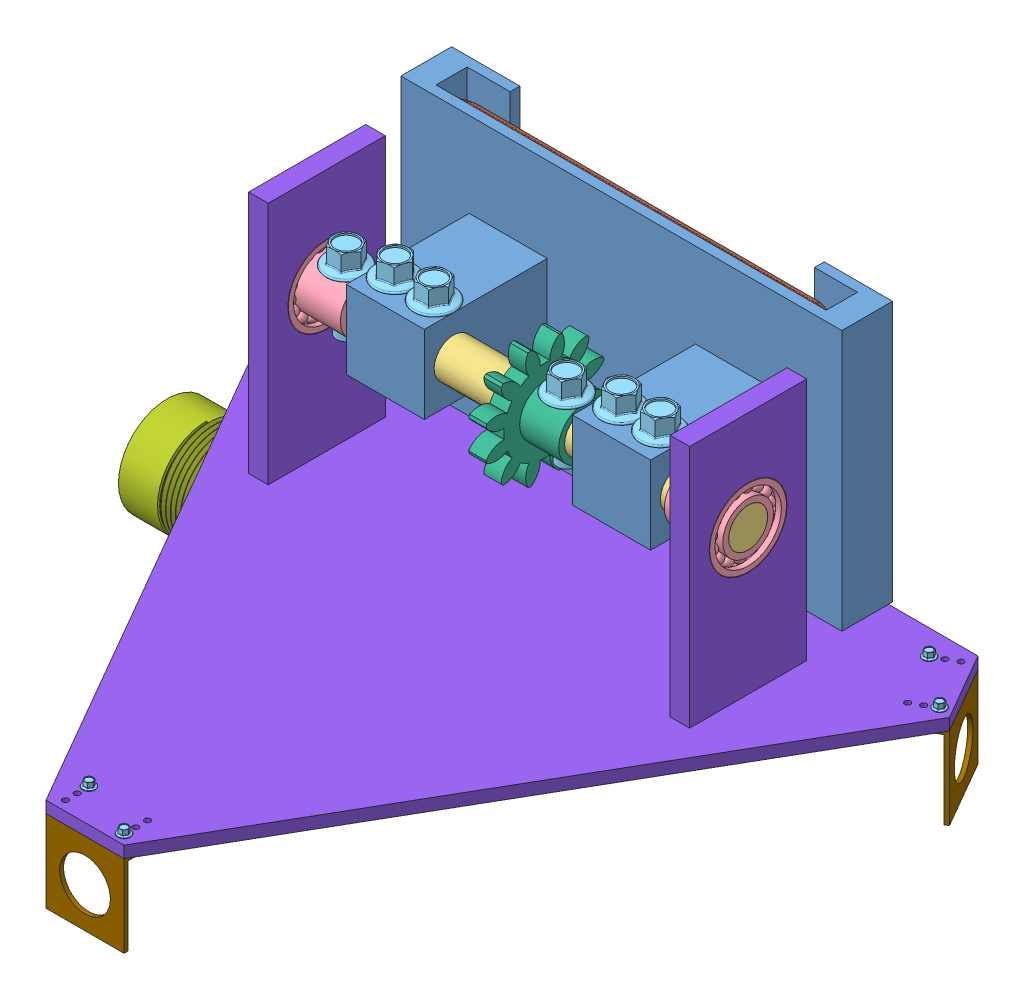
SolidWorks assembly Final Assembly, configuration Default. Lengths in mm.
Overall size (358.9 208.33 302.86).
26 component instances, 9 part files, 2 mates.
Components (placement in the parent):
- Assem2-1: Assem2 [Default] at (73.9795 152.7864 155.2771) size (297.05 208.33 104.25)
  - panpart1-1: panpart1 [Default] at (50.4862 130.7622 195.8282) size (226 133.5 89)
  - tablet-1: tablet [Default] at (50.8522 130.6632 215.8282) size (200.66 129.98 23.56)
  - shaft-1: shaft [Default] at (-62.5138 130.7622 269.8282) x (1 0 0) z (0 0 -1) size (226 20 20)
  - Bearing-1: Bearing [Default] at (-1.8143 116.4662 250.1482) size (30 40 40)
  - Bearing-2: Bearing [Default] at (102.7866 145.0582 250.1482) x (-1 0 0) z (0 0 1) size (30 40 40)
  - hex flange machine screw_am-1: hex flange machine screw_am [B18.6.7M - M10 x 1.5 x 30 Indented HFMS --30N] at (-42.5138 154.4622 269.8282) x (0 -1 0) z (0 0 1) size (40.7 21 21)
  - hex flange machine screw_am-2: hex flange machine screw_am [B18.6.7M - M10 x 1.5 x 30 Indented HFMS --30N] at (143.4862 154.4622 269.8282) x (0 -1 0) z (-0.357498 0 0.933914) size (40.7 21 21)
  - hex flange machine screw_am-3: hex flange machine screw_am [B18.6.7M - M10 x 1.5 x 30 Indented HFMS --30N] at (-17.5138 161.4622 269.8282) x (0 -1 0) z (-0.737651 0 0.675182) size (40.7 21 21)
  - hex flange machine screw_am-4: hex flange machine screw_am [B18.6.7M - M10 x 1.5 x 30 Indented HFMS --30N] at (2.4862 161.4622 269.8282) x (0 -1 0) z (0 0 1) size (40.7 21 21)
  - hex flange machine screw_am-5: hex flange machine screw_am [B18.6.7M - M10 x 1.5 x 30 Indented HFMS --30N] at (98.4862 161.4622 269.8282) x (0 -1 0) z (0 0 1) size (40.7 21 21)
  - hex flange machine screw_am-6: hex flange machine screw_am [B18.6.7M - M10 x 1.5 x 30 Indented HFMS --30N] at (118.4862 161.4622 269.8282) x (0 -1 0) z (0 0 1) size (40.7 21 21)
  - Gear-1: Gear [Default] at (321.6356 216.6863 318.7793) x (1 0 0) z (0 0 -1) size (28.89 60.5 60.5)
  - hex flange machine screw_am-8: hex flange machine screw_am [B18.6.7M - M10 x 1.5 x 30 Indented HFMS --30N] at (70.4862 154.4622 269.8282) x (0 -1 0) z (0 0 1) size (40.7 21 21)
  - worm-1: worm [Default] at (-113.563 14.8313 270.5485) size (110 50 52.57)
- Assem1-1: Assem1 [Default] at (5281.6766 -25045.8049 41757.6662) x (-1 0 0) z (0 0 -1) size (349.71 173 302.86)
  - Base-1: Base [Default] at (5157.2109 25249.3535 41296.0137) size (349.71 131 302.86)
  - LClamp-1: LClamp [Default] at (5001.4077 25249.3535 41362.8727) x (0.5 0 0.866025) z (0.866025 0 -0.5) size (40 42 22)
  - LClamp-2: LClamp [Default] at (5177.2109 25249.3535 41127.6547) x (-1 0 0) z (0 0 1) size (40 42 22)
  - LClamp-3: LClamp [Default] at (5293.0141 25249.3535 41397.5137) x (0.5 0 -0.866025) z (-0.866025 0 -0.5) size (40 42 22)
  - hex flange machine screw_am-1: hex flange machine screw_am [B18.6.7M - M3 x 0.5 x 10 Indented HFMS --10N] at (5172.2109 25258.5535 41122.6547) x (0 -1 0) z (0 0 1) size (13.2 6.4 6.4)
  - hex flange machine screw_am-2: hex flange machine screw_am [B18.6.7M - M3 x 0.5 x 10 Indented HFMS --10N] at (5142.2109 25258.5535 41110.6547) x (0 -1 0) z (0 0 1) size (13.2 6.4 6.4)
  - hex flange machine screw_am-3: hex flange machine screw_am [B18.6.7M - M3 x 0.5 x 10 Indented HFMS --10N] at (5314.8442 25258.5535 41369.7028) x (0 -1 0) z (0 0 1) size (13.2 6.4 6.4)
  - hex flange machine screw_am-4: hex flange machine screw_am [B18.6.7M - M3 x 0.5 x 10 Indented HFMS --10N] at (5310.2365 25258.5535 41401.6836) x (0 -1 0) z (0 0 1) size (13.2 6.4 6.4)
  - hex flange machine screw_am-5: hex flange machine screw_am [B18.6.7M - M3 x 0.5 x 10 Indented HFMS --10N] at (5014.5776 25258.5535 41395.6836) x (0 -1 0) z (0 0 1) size (13.2 6.4 6.4)
  - hex flange machine screw_am-6: hex flange machine screw_am [B18.6.7M - M3 x 0.5 x 10 Indented HFMS --10N] at (4989.1853 25258.5535 41375.7028) x (0 -1 0) z (0 0 1) size (13.2 6.4 6.4)
Mates (geometry in assembly coordinates):
- Concentric2: concentric anti-aligned: cylinder of Assem2-1/Bearing-1 through (-48.5343 283.5486 425.1048) axis (1 0 0) radius 20; cylinder of Assem1-1/Base-1 through (299.3214 283.5486 425.1048) axis (-1 0 0) radius 20
- Coincident2: coincident aligned: plane of Assem2-1/shaft-1 through (11.4657 283.5486 425.1054) normal (-1 0 0); plane of Assem1-1/Base-1 through (11.4657 334.5486 455.1048) normal (-1 0 0)
